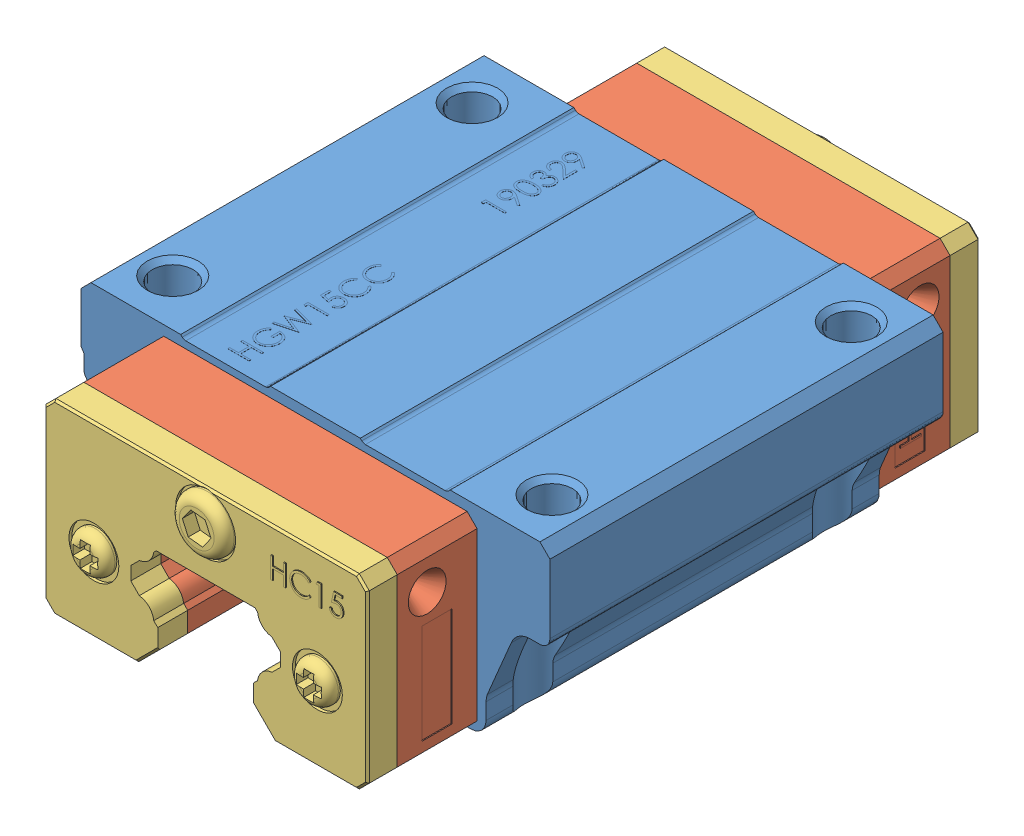
SolidWorks assembly HGW15CC, configuration По умолчанию. Lengths in mm.
Overall size (47 19.7 63.41).
5 component instances, 3 part files, 10 mates.
Components (placement in the parent):
- HGW15CC1-1: HGW15CC1 [По умолчанию] at origin size (47 19.7 39.4)
- HGW15CC2-1: HGW15CC2 [По умолчанию] at (0 0 39.4) size (32.4 18.7 8)
- HGW15CC2-2: HGW15CC2 [По умолчанию] x (-1 0 0) z (0 0 -1) size (32.4 18.7 8)
- HGW15CC3-1: HGW15CC3 [По умолчанию] at (0 0 -8) x (-1 0 0) z (0 0 -1) size (32.4 18.7 4)
- HGW15CC3-2: HGW15CC3 [По умолчанию] at (0 0 47.4) size (32.4 18.7 4)
Mates (geometry in assembly coordinates):
- Совпадение1: coincident anti-aligned: plane of HGW15CCZ0C_1-1 through (15.5982 1.5 39.4) normal (0 0 1); plane of HGW15CCZ0C_2-1 through (-6.8215 4.3367 39.4) normal (0 0 -1)
- Совпадение2: coincident aligned: plane of HGW15CCZ0C_1-1 through (-4.9495 10.7 39.4) normal (0 -1 0); plane of HGW15CCZ0C_2-1 through (-4.9495 10.7 47.4) normal (0 -1 0)
- Совпадение3: coincident aligned: plane of HGW15CCZ0C_1-1 through (-7.5 6.8093 39.4) normal (1 0 0); plane of HGW15CCZ0C_2-1 through (-7.5 6.8093 47.4) normal (1 0 0)
- Совпадение4: coincident anti-aligned: plane of HGW15CCZ0C_1-1 through (15.5982 1.5 0) normal (0 0 -1); plane of HGW15CCZ0C_2-2 through (6.8215 4.3367 0) normal (0 0 1)
- Совпадение5: coincident aligned: plane of HGW15CCZ0C_1-1 through (-4.9495 10.7 39.4) normal (0 -1 0); plane of HGW15CCZ0C_2-2 through (4.9495 10.7 -8) normal (0 -1 0)
- Совпадение6: coincident aligned: plane of HGW15CCZ0C_1-1 through (-7.5 6.8093 39.4) normal (1 0 0); plane of HGW15CCZ0C_2-2 through (-7.5 8.1495 -8) normal (1 0 0)
- Совпадение8: coincident anti-aligned: plane of HGW15CCZ0C_2-1 through (-6.8215 4.3367 47.4) normal (0 0 1); plane of HGW15CC3-2 through (-6.8215 4.3367 47.4) normal (0 0 -1)
- Концентричный2: concentric aligned: cylinder of HGW15CCZ0C_2-1 through (6.8215 10.6342 47.4) axis (0 0 -1) radius 1.63; cylinder of HGW15CC3-2 through (6.8215 10.6342 50.4) axis (0 0 -1) radius 1.63
- Концентричный3: concentric aligned: cylinder of HGW15CCZ0C_2-2 through (-6.8215 10.6342 -8) axis (0 0 1) radius 1.63; cylinder of HGW15CC3-1 through (-6.8215 10.6342 -11) axis (0 0 1) radius 1.63
- Совпадение9: coincident aligned: line of HGW15CCZ0C_2-2 through (16.2 17.7 -8) axis (0 -1 0); line of HGW15CC3-1 through (16.2 17.7 -8) axis (0 -1 0)
